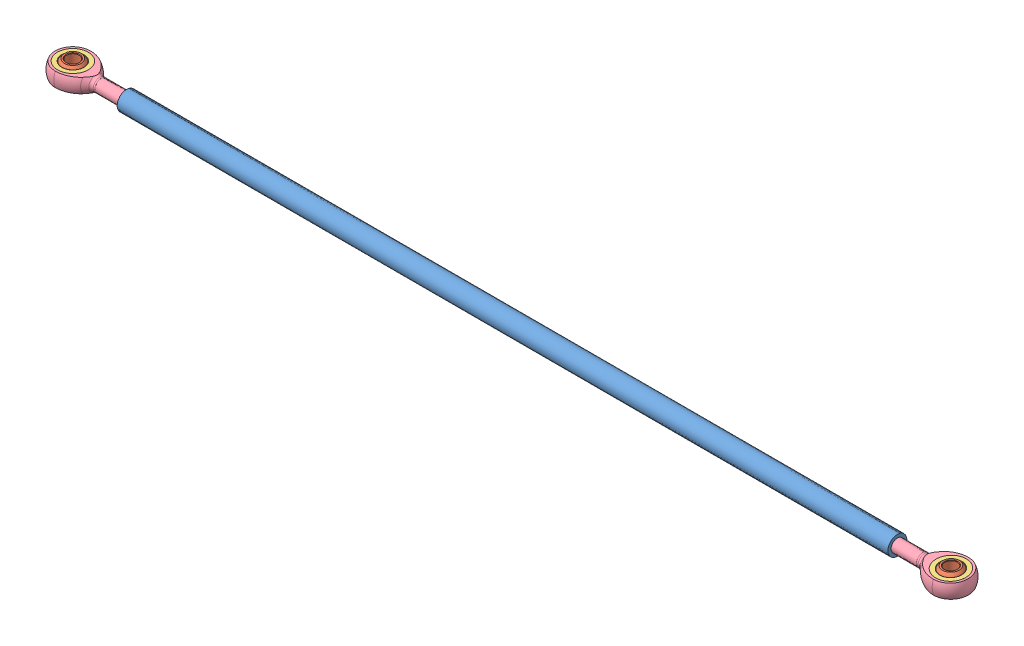
SolidWorks assembly Front Steering Rod, configuration Default. Lengths in mm.
Overall size (461.07 21.17 22.9).
9 component instances, 4 part files, 4 mates.
Components (placement in the parent):
- Front Steering Rod-1: Front Steering Rod [Default<As Machined>] at (-78.1796 203.3649 310.9198) size (386.47 9.53 9.53)
- MM-4T Rod End-1: MM-4T Rod End [Default] at (-65.4981 202.8203 312.0011) x (-0.027485 -0.01683 0.999481) z (-0.999534 0.013727 -0.027255) size (21.2 20.13 49.97) (flexible)
  - MM-4T Ball-1: MM-4T Ball [Default] at origin size (12.7 12.7 12.7)
  - MM-4T Sleeve-1: MM-4T Sleeve [Default] at (-1.0904 0.5261 0.0185) x (0.999384 0.022203 -0.027186) z (0.027485 -0.013262 0.999534) size (15.44 7.14 15.44)
  - MM-4T Housing-1: MM-4T Housing [Default] at (-1.0904 0.5261 0.0185) x (0.999384 0.022203 -0.027186) z (0.027485 -0.013262 0.999534) size (19.45 19.05 49.2)
- MM-4T Rod End-2: MM-4T Rod End [Default] at (295.6132 202.8531 309.8225) x (0.027485 0.013262 -0.999534) z (0.999534 0.012901 0.027656) size (21.2 20.13 49.97) (flexible)
  - MM-4T Ball-1: MM-4T Ball [Default] at origin size (12.7 12.7 12.7)
  - MM-4T Sleeve-1: MM-4T Sleeve [Default] at (-1.0904 0.5261 0.0185) x (0.999384 0.022203 -0.027186) z (0.027485 -0.013262 0.999534) size (15.44 7.14 15.44)
  - MM-4T Housing-1: MM-4T Housing [Default] at (-1.0904 0.5261 0.0185) x (0.999384 0.022203 -0.027186) z (0.027485 -0.013262 0.999534) size (19.45 19.05 49.2)
Mates (geometry in assembly coordinates):
- Concentric1: concentric aligned: cylinder of Front Steering Rod-1 through (308.2947 203.3649 310.9198) axis (-1 0 0) radius 4.7625; cylinder of MM-4T Rod End-2/MM-4T Housing-1 through (308.5474 203.3649 310.9198) axis (-1 0 0) radius 3.175
- Concentric2: concentric anti-aligned: cylinder of Front Steering Rod-1 through (308.2947 203.3649 310.9198) axis (-1 0 0) radius 4.7625; cylinder of ? through (-78.4324 203.3649 310.9198) axis (1 0 0) radius 3.175
- Coincident1: coincident: point of Front Steering Rod-1; point of MM-4T Rod End-1/MM-4T Ball-1
- Coincident2: coincident: point of Front Steering Rod-1; point of MM-4T Rod End-2/MM-4T Ball-1
